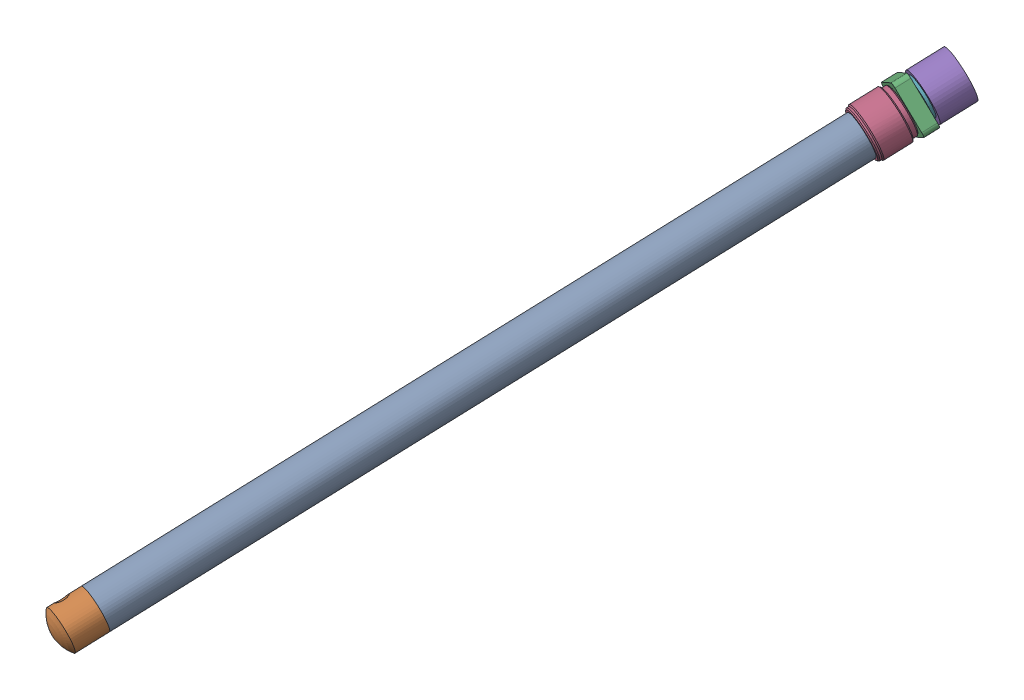
SolidWorks assembly Ensemble Tige, configuration Défaut. Lengths in mm.
Overall size (133.59 147.97 333.57).
7 component instances, 7 part files, 12 mates.
Components (placement in the parent):
- Tige de vérin-1: Tige de vérin [Défaut] at (-298.0614 -132.433 363.5002) x (-0.701442 -0.555361 -0.446713) z (0.298295 0.340479 -0.891681) size (18 18 305)
- Nez vérin-1: Nez vérin [Défaut] at (-333.085 -172.4094 468.1946) x (-0.298295 -0.340479 0.891681) z (0.699722 0.557372 0.446906) size (29 18 18)
- Guide ecrou-1: Guide ecrou [Défaut] at (-205.0112 -15.4431 71.9036) x (0.701442 0.555361 0.446713) z (-0.298295 -0.340479 0.891681) size (21.55 21.55 6.3)
- Ecrou à billes-1: Ecrou à billes [Défaut] at (-203.5858 -4.3549 55.9233) x (0.298295 0.340479 -0.891681) z (0.701442 0.555361 0.446713) size (44.4 22 22)
- Butée arrière-1: Butée arrière [Défaut] at (-195.5928 -15.4737 57.1955) x (0.298295 0.340479 -0.891681) z (0.884079 0.25356 0.392571) size (15 21.5 21.5)
- Joint torique 2-1: Joint torique 2 [Défaut] at (-201.644 -22.3806 75.284) x (0.298295 0.340479 -0.891681) z (0.874683 0.276411 0.398154) size (2 18.2 18.2)
- anneau elastique-1: anneau elastique [B27.8M - 3DM1-14] at (-200.1907 -20.7219 70.9398) x (0.952962 -0.053689 0.298295) z (-0.298295 -0.340479 0.891681) size (16.83 18.54 1.3)
Mates (geometry in assembly coordinates):
- Coaxial1: concentric aligned: cylinder of Guide ecrou-1 through (-209.6259 -31.4913 99.144) axis (-0.298295 -0.340479 0.891681) radius 7.1; cylinder of Ecrou à billes-1 through (-209.766 -31.6513 99.5628) axis (-0.298295 -0.340479 0.891681) radius 7.1
- Coïncidente7: coincident anti-aligned: plane of Guide ecrou-1 through (-202.2192 -23.0371 77.0033) normal (-0.298295 -0.340479 0.891681); plane of Ecrou à billes-1 through (-182.6573 -45.966 74.7922) normal (0.298295 0.340479 -0.891681)
- Coïncidente8: coincident anti-aligned: plane of Tige de vérin-1 through (-207.0814 -28.5869 91.5377) normal (0.298295 0.340479 -0.891681); plane of Ecrou à billes-1 through (-187.5195 -51.5158 89.3266) normal (-0.298295 -0.340479 0.891681)
- Coaxial3: concentric aligned: cylinder of Tige de vérin-1 through (-207.0814 -28.5869 91.5377) axis (-0.298295 -0.340479 0.891681) radius 9; cylinder of Ecrou à billes-1 through (-209.766 -31.6513 99.5628) axis (-0.298295 -0.340479 0.891681) radius 8
- Coaxial4: concentric anti-aligned: cylinder of Tige de vérin-1 through (-207.0814 -28.5869 91.5377) axis (-0.298295 -0.340479 0.891681) radius 9; cylinder of Nez vérin-1 through (-294.4819 -128.3472 352.8001) axis (0.298295 0.340479 -0.891681) radius 9
- Coïncidente9: coincident anti-aligned: plane of Tige de vérin-1 through (-298.0614 -132.433 363.5002) normal (-0.298295 -0.340479 0.891681); plane of Nez vérin-1 through (-292.219 -139.2481 362.8524) normal (0.298295 0.340479 -0.891681)
- Coaxial6: concentric aligned: cylinder of Ecrou à billes-1 through (-209.766 -31.6513 99.5628) axis (-0.298295 -0.340479 0.891681) radius 7.1; cylinder of Butée arrière-1 through (-205.3879 -26.6539 86.4753) axis (-0.298295 -0.340479 0.891681) radius 7.1
- Coïncidente13: coincident anti-aligned: line of Joint torique 2-1 through (-215.0477 -37.6799 115.3511) axis (0.298295 0.340479 -0.891681); line of assembly
- Parallèle1: parallel: plane of Guide ecrou-1; line of assembly
- Coaxial9: concentric aligned: cylinder of Ecrou à billes-1 through (-209.766 -31.6513 99.5628) axis (-0.298295 -0.340479 0.891681) radius 6.7; cylinder of anneau elastique-1 through (-199.803 -20.2793 69.7807) axis (-0.298295 -0.340479 0.891681) radius 6.575
- Coïncidente15: coincident anti-aligned: circle of Ecrou à billes-1; plane of anneau elastique-1 through (-199.803 -20.2793 69.7807) normal (0.298295 0.340479 -0.891681)
- Coïncidente16: coincident anti-aligned: plane of Butée arrière-1 through (-202.3572 -13.8508 71.3808) normal (-0.298295 -0.340479 0.891681); plane of anneau elastique-1 through (-199.803 -20.2793 69.7807) normal (0.298295 0.340479 -0.891681)
